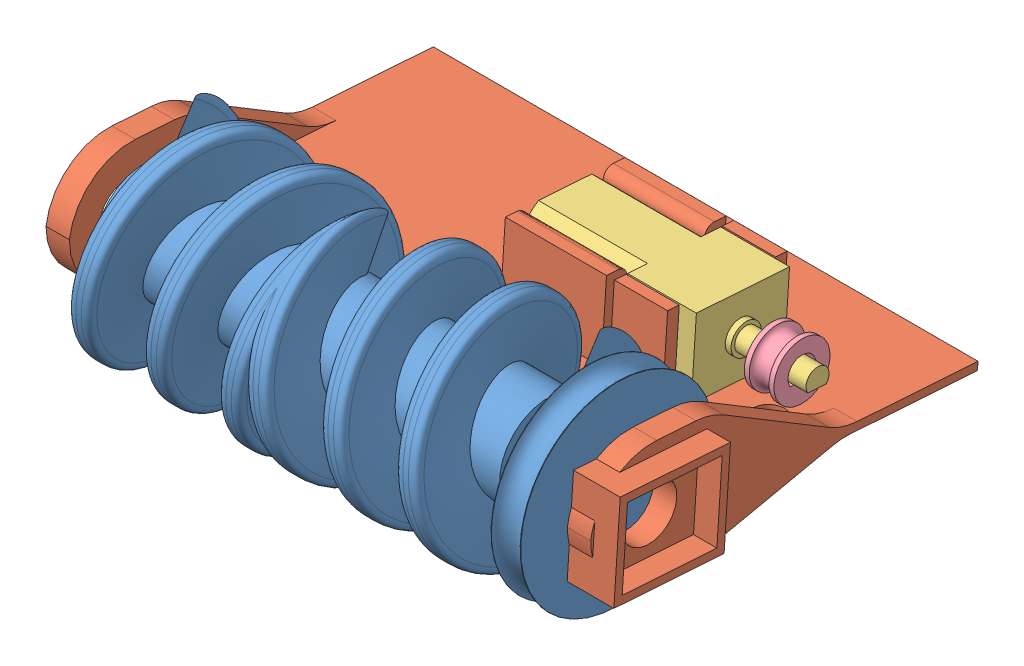
SolidWorks assembly Drone, configuration Default. Lengths in mm.
Overall size (73 36.46 60.57).
4 component instances, 4 part files, 9 mates.
Components (placement in the parent):
- drone brush 1-1: drone brush 1 [Default] at (-49.594 50.7039 24.959) x (1 0 0) z (0 -0.420711 0.907195) size (62.04 26.67 29.15)
- Drone frame2-1: Drone frame2 [Default] at (14.406 48.7209 32.612) x (1 0 0) z (0 0.068161 0.997674) size (73 15.85 49.98)
- micro dc motor-1: micro dc motor [Default] at (-20.364 52.5191 1.2802) x (0 0.068161 0.997674) z (0 0.997674 -0.068161) size (12 33.91 9.85)
- Part3^Drone-1: Part3^Drone [Default] at (12.406 52.5191 1.2802) x (0 0.068161 0.997674) z (1 0 0) size (7.2 7.2 5.81) (virtual)
Mates (geometry in assembly coordinates):
- Concentric1: concentric: cylinder of drone brush 1-1 through (-7.594 50.7039 24.959) axis (1 0 0) radius 1.25; cylinder of Drone frame2-1 through (14.406 50.7039 24.959) axis (-1 0 0) radius 3.6
- Coincident2: coincident: plane of Drone frame2-1 through (14.406 49.7186 32.5438) normal (0 0.997674 -0.068161); plane of micro dc motor-1 through (-6.364 47.372 -1.8031) normal (0 -0.997674 0.068161)
- Distance1: distance = 13 mm: plane of micro dc motor-1 through (2.486 47.1966 -4.3701) normal (0 -0.068161 -0.997674); plane of Drone frame2-1 through (-55.594 46.3105 -17.3399) normal (0 -0.068161 -0.997674)
- InPlace1: in place: plane of ? through (53.957 40.9212 30.9883) normal (1 0 0); plane of ? through (53.957 0 0) normal (1 0 0); moOrthogonalPlaneRef_w of ? through (53.957 40.9212 30.9883) normal (1 0 0); plane of ? through (53.957 0 0) normal (0 1 0); plane of ? through (53.957 40.9212 30.9883) normal (1 0 0); plane of ? through (53.957 0 0) normal (0 0 -1); plane of micro dc motor-1 through (12.406 52.5191 1.2802) normal (1 0 0); unknown of Part3^Drone-1
- Coincident4: coincident: plane of micro dc motor-1; plane of Part3^Drone-1
- Coincident5: coincident: moOrthogonalPlaneRef_w of micro dc motor-1 through (12.406 52.5191 1.2802) normal (0 -0.997674 0.068161); plane of Part3^Drone-1 through (12.406 52.5191 1.2802) normal (0 -0.997674 0.068161)
- Coincident6: coincident: moOrthogonalPlaneRef_w of micro dc motor-1 through (12.406 52.5191 1.2802) normal (0 -0.068161 -0.997674); plane of Part3^Drone-1 through (12.406 52.5191 1.2802) normal (0 0.068161 0.997674)
- Coincident7: coincident: plane of drone brush 1-1 through (10.406 50.7039 24.959) normal (1 0 0); plane of Part3^Drone-1 through (10.406 52.5191 1.2802) normal (1 0 0)
- Distance2: distance = 2 mm: plane of drone brush 1-1 through (-50.594 50.7039 24.959) normal (-1 0 0); plane of Drone frame2-1 through (-52.594 58.6976 31.9304) normal (1 0 0)
